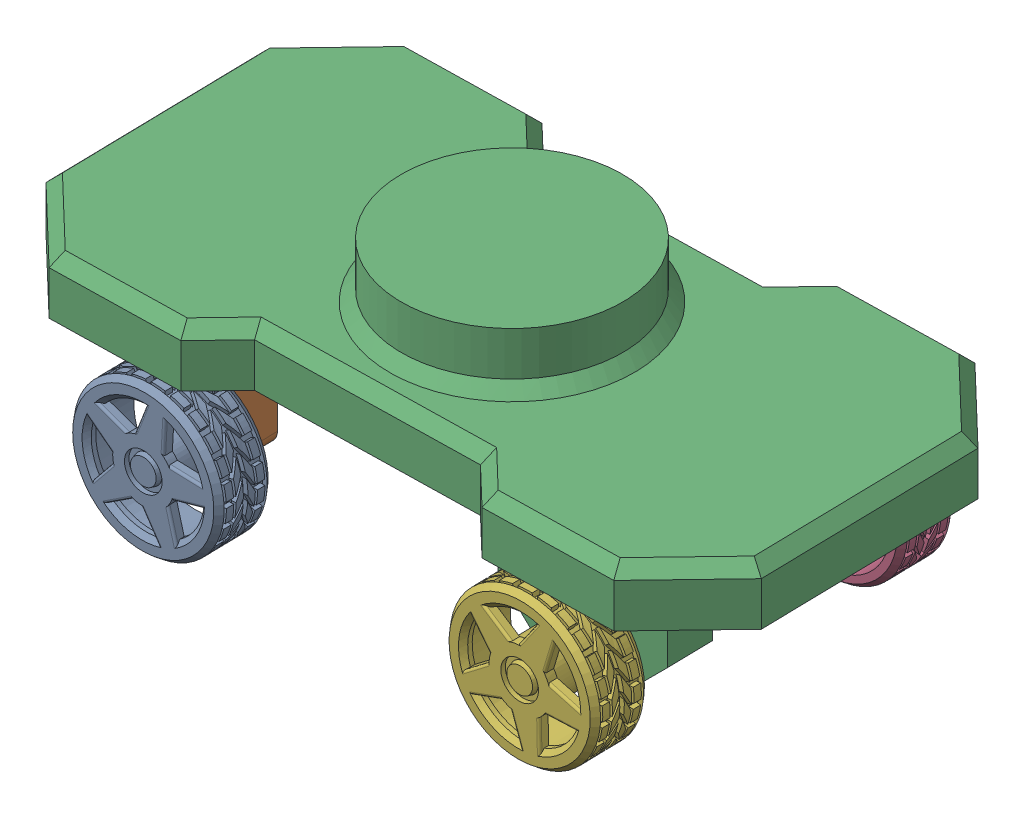
SolidWorks assembly carassembly, configuration Default. Lengths in mm.
Overall size (975.54 411.86 527.93).
7 component instances, 3 part files, 13 mates.
Components (placement in the parent):
- carwheel-1: carwheel [Default] at (-177.9351 -17.7945 169.2719) x (0.500471 0.865691 -0.010395) z (0.020767 0 0.999784) size (203.2 203.2 76.59)
- frontwheelaxis-1: frontwheelaxis [Default] at (-178.1988 -17.7945 156.5746) x (0.999784 0 -0.020767) z (0.020767 0 0.999784) size (69.85 209.55 133.35)
- carchassis-1: carchassis [Default] at (71.4015 140.9555 -51.8537) x (0.999784 0 -0.020767) z (0.020767 0 0.999784) size (965.2 304.8 508)
- carwheel-2: carwheel [Default] at (320.8632 -17.7945 -272.9819) x (-0.999784 0 0.020767) z (-0.020767 0 -0.999784) size (203.2 203.2 76.59)
- carwheel-3: carwheel [Default] at (-187.1525 -17.7945 -262.4298) x (-0.94064 -0.338842 0.019538) z (-0.020767 0 -0.999784) size (203.2 203.2 76.59)
- carwheel-4: carwheel [Default] at (329.8302 -17.7945 158.725) x (-0.134735 -0.990878 0.002799) z (0.020767 0 0.999784) size (203.2 203.2 76.59)
- frontwheelaxis-2: frontwheelaxis [Default] at (-186.8887 -17.7945 -249.7325) x (-0.999784 0 0.020767) z (-0.020767 0 -0.999784) size (69.85 209.55 133.35)
Mates (geometry in assembly coordinates):
- Parallel1: parallel anti-aligned: plane of frontwheelaxis-1 through (-215.3513 -49.5445 55.7244) normal (0 -1 0)
- Coincident2: coincident anti-aligned: plane of carwheel-1 through (-177.5394 -17.7945 188.3178) normal (-0.020767 0 -0.999784); plane of frontwheelaxis-1 through (-177.5394 -17.7945 188.3178) normal (0.020767 0 0.999784)
- Concentric1: concentric anti-aligned: cylinder of carwheel-1 through (-177.1438 -17.7945 207.3637) axis (0.020767 0 0.999784) radius 25.4; cylinder of frontwheelaxis-1 through (-177.5394 -17.7945 188.3178) axis (-0.020767 0 -0.999784) radius 25.4
- Coincident3: coincident anti-aligned: plane of frontwheelaxis-1 through (-179.7086 160.0055 89.9166) normal (0 1 0); plane of carchassis-1 through (-179.7086 160.0055 89.9166) normal (0 -1 0)
- Concentric2: concentric aligned: cylinder of frontwheelaxis-1 through (-179.7086 160.0055 89.9166) axis (0 -1 0) radius 25.4; cylinder of carchassis-1 through (-179.7086 160.0055 89.9166) axis (0 -1 0) radius 25.4
- Coincident5: coincident anti-aligned: plane of carchassis-1 through (-185.3789 160.0055 -183.0745) normal (0 -1 0); plane of frontwheelaxis-2 through (-185.3789 160.0055 -183.0745) normal (0 1 0)
- Concentric3: concentric aligned: cylinder of carchassis-1 through (-185.3789 160.0055 -183.0745) axis (0 -1 0) radius 25.4; cylinder of frontwheelaxis-2 through (-185.3789 160.0055 -183.0745) axis (0 -1 0) radius 25.4
- Coincident6: coincident anti-aligned: plane of carwheel-3 through (-187.5481 -17.7945 -281.4757) normal (0.020767 0 0.999784); plane of frontwheelaxis-2 through (-187.5481 -17.7945 -281.4757) normal (-0.020767 0 -0.999784)
- Concentric4: concentric anti-aligned: cylinder of carwheel-3 through (-187.9437 -17.7945 -300.5216) axis (-0.020767 0 -0.999784) radius 25.4; cylinder of frontwheelaxis-2 through (-187.5481 -17.7945 -281.4757) axis (0.020767 0 0.999784) radius 25.4
- Coincident7: coincident anti-aligned: plane of carchassis-1 through (330.2258 -17.7945 177.7709) normal (0.020767 0 0.999784); plane of carwheel-4 through (330.2258 -17.7945 177.7709) normal (-0.020767 0 -0.999784)
- Concentric5: concentric anti-aligned: cylinder of carchassis-1 through (330.2258 -17.7945 177.7709) axis (-0.020767 0 -0.999784) radius 25.4; cylinder of carwheel-4 through (330.6214 -17.7945 196.8168) axis (0.020767 0 0.999784) radius 25.4
- Coincident8: coincident anti-aligned: plane of carchassis-1 through (320.4676 -17.7945 -292.0277) normal (-0.020767 0 -0.999784); plane of carwheel-2 through (320.4676 -17.7945 -292.0277) normal (0.020767 0 0.999784)
- Concentric6: concentric anti-aligned: cylinder of carchassis-1 through (320.4676 -17.7945 -292.0277) axis (0.020767 0 0.999784) radius 25.4; cylinder of carwheel-2 through (320.072 -17.7945 -311.0736) axis (-0.020767 0 -0.999784) radius 25.4
